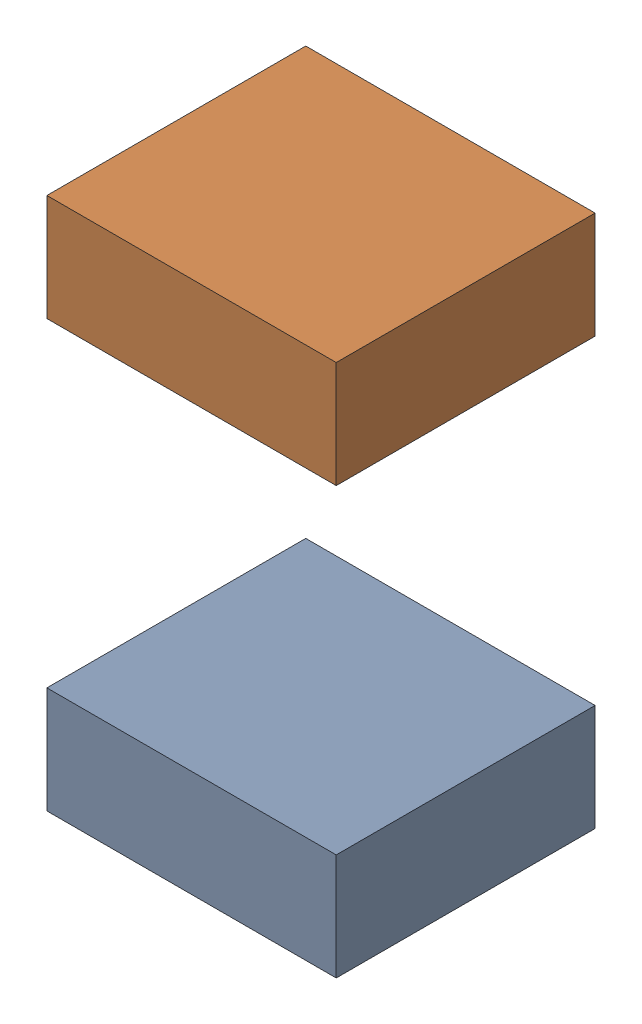
SolidWorks assembly C2, configuration 默认. Lengths in mm.
Overall size (0.95 1.75 0.85).
5 component instances, 1 part files, 0 mates.
Components (placement in the parent):
- 6241791616-1: 6241791616 [默认] at (11.43 25.019 0) (suppressed, hidden)
- 6241792176-1: 6241792176 [默认] at (11.43 24.319 0) size (0.95 0.35 0.85)
  - Extruded-1-1: Extruded-1 [默认] at origin size (0.95 0.35 0.85)
- 6241792176-2: 6241792176 [默认] at (11.43 25.719 0) size (0.95 0.35 0.85)
  - Extruded-1-1: Extruded-1 [默认] at origin size (0.95 0.35 0.85)
